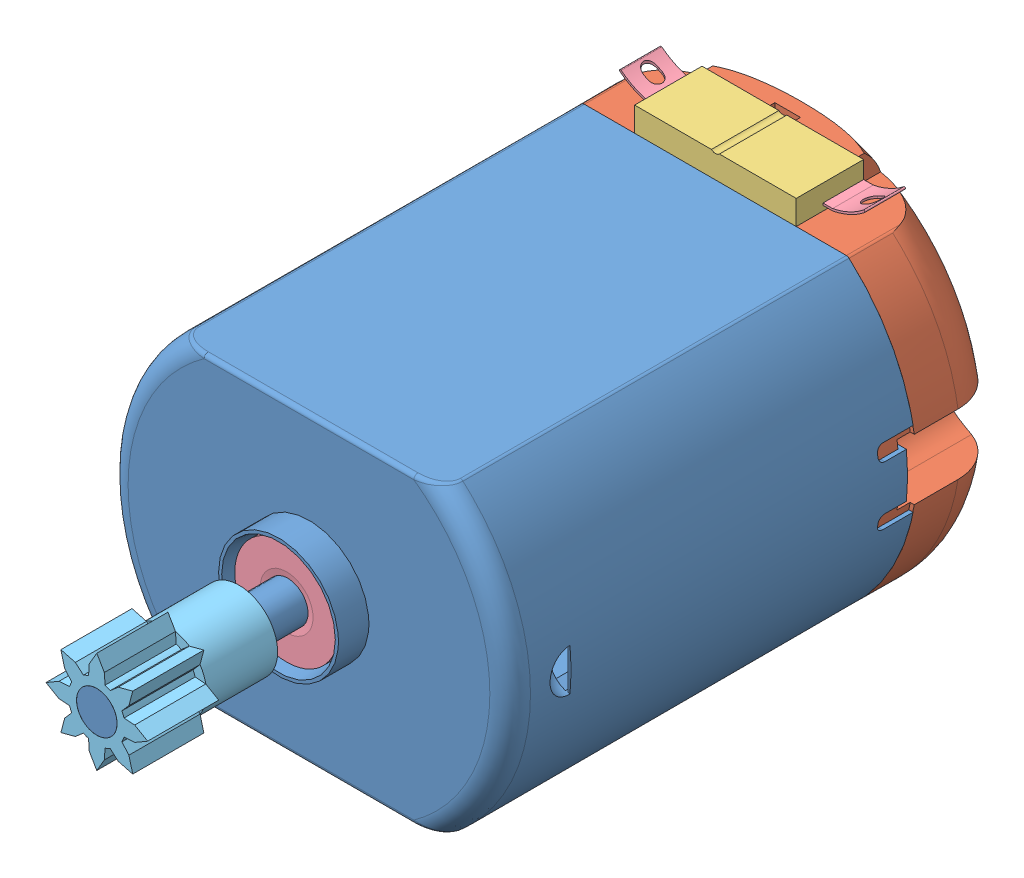
SolidWorks assembly MotorReductorYellow, configuration Default. Lengths in mm.
Overall size (19.85 16.19 38.5).
5 component instances, 5 part files, 16 mates.
Components (placement in the parent):
- MotorReductorYellow01-1: MotorReductorYellow01 [Default] at origin size (19.8 15.08 38.5)
- MotorReductorYellow02-1: MotorReductorYellow02 [Default] at (0 0 -9.3539) size (19.85 16.1 11.4)
- Part4^MotorReductorYellow-1: Part4^MotorReductorYellow [Default] at (0 0 -13.3161) size (7.95 1.2 3.32) (virtual)
- MotorReductorYellow04-1: MotorReductorYellow04 [Default] at (0 0 -13.3161) size (12.07 11.04 24.42)
- MotorReductorYellow03-1: MotorReductorYellow03 [Default] at (0 0 20.4408) size (5 5 7)
Mates (geometry in assembly coordinates):
- InPlace2: in place: plane of MotorReductorYellow01-1 through (-9.625 -1.1095 -9.3539) normal (0 0 1); plane of MotorReductorYellow02-1 through (0 0 -9.3539) normal (0 0 1); moOrthogonalPlaneRef_w of MotorReductorYellow01-1 through (-9.625 -1.1095 -9.3539) normal (0 0 1); plane of MotorReductorYellow02-1 through (0 0 -9.3539) normal (0 1 0); plane of MotorReductorYellow01-1 through (-9.625 -1.1095 -9.3539) normal (0 0 1); plane of MotorReductorYellow02-1 through (0 0 -9.3539) normal (1 0 0); plane of MotorReductorYellow01-1 through (-9.625 -1.1095 -9.3539) normal (0 0 1); unknown of MotorReductorYellow02-1
- Coincident4: coincident aligned: plane of MotorReductorYellow01-1; plane of MotorReductorYellow02-1
- Coincident5: coincident aligned: moOrthogonalPlaneRef_w of MotorReductorYellow01-1 through (0 0 -9.3539) normal (0 1 0); plane of MotorReductorYellow02-1 through (0 0 -9.3539) normal (0 1 0)
- Coincident6: coincident anti-aligned: moOrthogonalPlaneRef_w of MotorReductorYellow01-1 through (0 0 -9.3539) normal (-1 0 0); plane of MotorReductorYellow02-1 through (0 0 -9.3539) normal (1 0 0)
- InPlace3: in place: plane of MotorReductorYellow02-1 through (3.725 8.65 -13.3161) normal (0 0 1); plane of ? through (0 0 -13.3161) normal (0 0 1); plane of MotorReductorYellow02-1 through (3.725 8.65 -13.3161) normal (0 0 1); plane of ? through (0 0 -13.3161) normal (0 1 0); plane of MotorReductorYellow02-1 through (3.725 8.65 -13.3161) normal (0 0 1); plane of ? through (0 0 -13.3161) normal (1 0 0); plane of MotorReductorYellow02-1 through (3.725 8.65 -13.3161) normal (0 0 1); unknown of ?
- Coincident7: coincident aligned: plane of MotorReductorYellow02-1; plane of Part4^MotorReductorYellow-1
- Coincident8: coincident aligned: moOrthogonalPlaneRef_w of MotorReductorYellow02-1 through (0 0 -13.3161) normal (0 1 0); plane of Part4^MotorReductorYellow-1 through (0 0 -13.3161) normal (0 1 0)
- Coincident9: coincident anti-aligned: moOrthogonalPlaneRef_w of MotorReductorYellow02-1 through (0 0 -13.3161) normal (-1 0 0); plane of Part4^MotorReductorYellow-1 through (0 0 -13.3161) normal (1 0 0)
- InPlace4: in place: plane of MotorReductorYellow02-1 through (3.725 8.65 -13.3161) normal (0 0 1); plane of ? through (0 0 -13.3161) normal (0 0 1); plane of MotorReductorYellow02-1 through (3.725 8.65 -13.3161) normal (0 0 1); plane of ? through (0 0 -13.3161) normal (0 1 0); plane of MotorReductorYellow02-1 through (3.725 8.65 -13.3161) normal (0 0 1); plane of ? through (0 0 -13.3161) normal (1 0 0); plane of MotorReductorYellow02-1 through (3.725 8.65 -13.3161) normal (0 0 1); unknown of ?
- Coincident10: coincident aligned: plane of MotorReductorYellow02-1; plane of MotorReductorYellow04-1
- Coincident11: coincident aligned: moOrthogonalPlaneRef_w of MotorReductorYellow02-1 through (0 0 -13.3161) normal (0 1 0); plane of MotorReductorYellow04-1 through (0 0 -13.3161) normal (0 1 0)
- Coincident12: coincident anti-aligned: moOrthogonalPlaneRef_w of MotorReductorYellow02-1 through (0 0 -13.3161) normal (-1 0 0); plane of MotorReductorYellow04-1 through (0 0 -13.3161) normal (1 0 0)
- InPlace5: in place: plane of MotorReductorYellow01-1 through (0 0 20.4408) normal (0 0 1); plane of MotorReductorYellow03-1 through (0 0 20.4408) normal (0 0 1); plane of MotorReductorYellow01-1 through (0 0 20.4408) normal (0 0 1); plane of MotorReductorYellow03-1 through (0 0 20.4408) normal (0 1 0); plane of MotorReductorYellow01-1 through (0 0 20.4408) normal (0 0 1); plane of MotorReductorYellow03-1 through (0 0 20.4408) normal (1 0 0); plane of MotorReductorYellow01-1 through (0 0 20.4408) normal (0 0 1); unknown of MotorReductorYellow03-1
- Coincident13: coincident aligned: plane of MotorReductorYellow01-1; plane of MotorReductorYellow03-1
- Coincident14: coincident aligned: moOrthogonalPlaneRef_w of MotorReductorYellow01-1 through (0 0 20.4408) normal (0 1 0); plane of MotorReductorYellow03-1 through (0 0 20.4408) normal (0 1 0)
- Coincident15: coincident anti-aligned: moOrthogonalPlaneRef_w of MotorReductorYellow01-1 through (0 0 20.4408) normal (-1 0 0); plane of MotorReductorYellow03-1 through (0 0 20.4408) normal (1 0 0)
